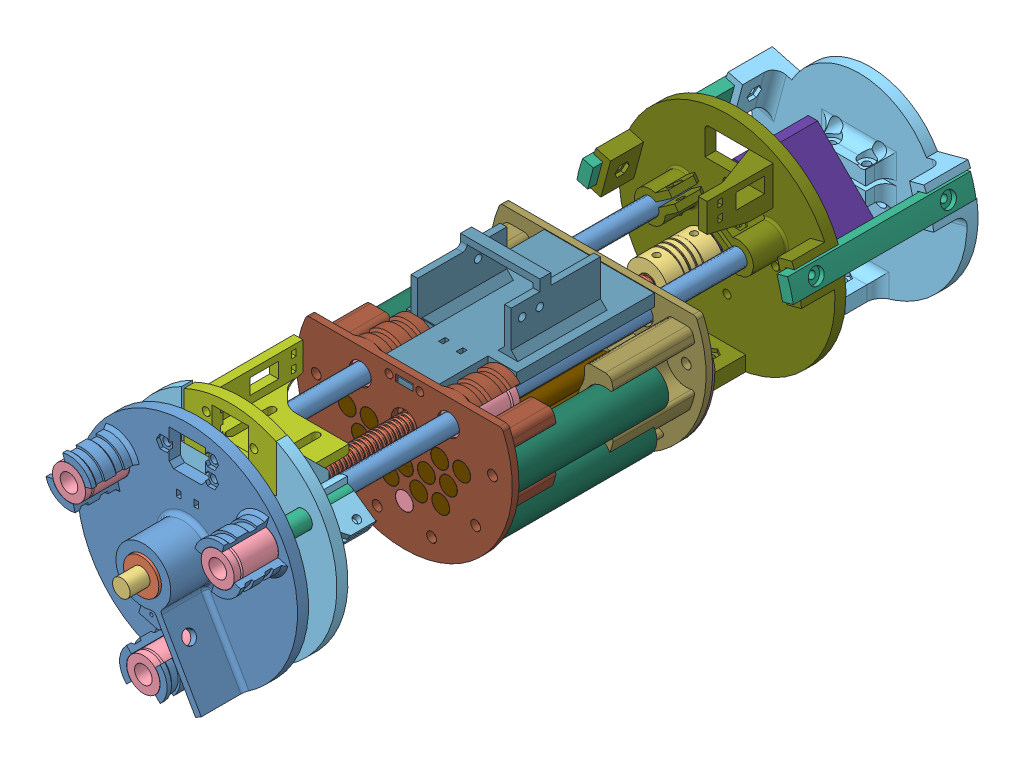
SolidWorks assembly Adjustment cabin, configuration 默认. Lengths in mm.
Overall size (100 100 340).
54 component instances, 25 part files, 87 mates.
Components (placement in the parent):
- Pogo_header_front_mount-1: Pogo_header_front_mount [默认] at (299.7292 -3.7239 87.5) size (100 100 25)
- F8-16M-1: F8-16M [默认] at (119.7292 -3.7239 108.5) x (1 0 0) z (0 -1 0) size (16 5 16)
- M8_bolt_40mm-2: M8_bolt_40mm [默认] at (-30.2708 -3.7239 78.5) x (1 0 0) z (0 -1 0) size (13 44 13)
- F8-16M-2: F8-16M [默认] at (119.7292 -3.7239 82.5) x (1 0 0) z (0 -1 0) size (16 5 16)
- LM8UU-1: LM8UU [默认] at (25.9542 15.7761 88.5) x (1 0 0) z (0 -1 0) size (15 24 15)
- LM8UU-2: LM8UU [默认] at (3.5042 -36.1854 88.5) x (-0.5 -0.866025 0) z (-0.866025 0.5 0) size (15 24 15)
- LM8UU-3: LM8UU [默认] at (-30.2708 9.2376 88.5) x (-0.5 0.866025 0) z (0.866025 0.5 0) size (15 24 15)
- Pogo_header_slider_mount-1: Pogo_header_slider_mount [默认] at (-300.2708 -153.7239 73.6245) x (-1 0 0) z (0 0 -1) size (98 93.03 21)
- 8mm_smooth_rod_45mm-1: 8mm_smooth_rod_45mm [默认] at (-26.4958 15.7761 98.6245) x (1 0 0) z (0 -1 0) size (8 45 8)
- 8mm_smooth_rod_45mm-2: 8mm_smooth_rod_45mm [默认] at (-4.0458 -36.1854 98.6245) x (-0.5 0.866025 0) z (0.866025 0.5 0) size (8 45 8)
- 8mm_smooth_rod_45mm-3: 8mm_smooth_rod_45mm [默认] at (29.7292 9.2376 98.6245) x (-0.5 -0.866025 0) z (-0.866025 0.5 0) size (8 45 8)
- Pogo_header_back_mount-2: Pogo_header_back_mount [默认] at (-449.7708 32.2761 73.6245) x (-1 0 0) z (0 0 -1) size (42 26 50)
- Acme_bearing_back-2: Acme_bearing_back [默认] at (-450.2708 -153.7239 68.6245) x (-1 0 0) z (0 0 -1) size (36.44 35.5 10)
- 608ZZ-1: 608ZZ [默认] at (-30.2708 -3.7239 55.6245) x (-1 0 0) z (0 1 0) size (22 7 22)
- Acme_bearing_front-1: Acme_bearing_front [默认] at (-450.2708 -303.7239 55.6245) x (-1 0 0) z (0 0 -1) size (36.44 35.5 16)
- Battery_mount_bearings-1: Battery_mount_bearings [默认] at (-0.2708 -3.7239 -6.0228) x (-1 0 0) z (0 0 -1) size (98 69.8 25)
- Battery_mount_acme-1: Battery_mount_acme [默认] at (-0.2708 -153.7239 -97.0228) size (98 69.8 40)
- Battery_rods_cover-1: Battery_rods_cover [默认] at (599.7292 -3.7239 -98.0228) size (98 58 1)
- Battery_mount_connector-1: Battery_mount_connector [默认] at (150.2292 11.2761 98.4772) x (1 0 0) z (0 1 0) size (50 91 30)
- LM8UU-4: LM8UU [默认] at (79.7292 6.2761 -31.0228) x (1 0 0) z (0 -1 0) size (15 24 15)
- LM8UU-5: LM8UU [默认] at (39.7292 6.2761 -31.0228) x (1 0 0) z (0 -1 0) size (15 24 15)
- 18650-1: 18650 [默认] at (-30.2708 -3.7239 -77.0228) x (1 0 0) z (0 -1 0) size (18 68 18)
- 18650-7: 18650 [默认] at (-26.2516 11.2761 -77.0228) x (0.866025 -0.5 0) z (-0.5 -0.866025 0) size (18 68 18)
- 18650-8: 18650 [默认] at (-15.2708 22.2569 -77.0228) x (0.5 -0.866025 0) z (-0.866025 -0.5 0) size (18 68 18)
- 18650-9: 18650 [默认] at (-0.2708 26.2761 -77.0228) x (0 -1 0) z (-1 0 0) size (18 68 18)
- 18650-10: 18650 [默认] at (14.7292 22.2569 -77.0228) x (-0.5 -0.866025 0) z (-0.866025 0.5 0) size (18 68 18)
- 18650-11: 18650 [默认] at (25.7099 11.2761 -77.0228) x (-0.866025 -0.5 0) z (-0.5 0.866025 0) size (18 68 18)
- 18650-12: 18650 [默认] at (29.7292 -3.7239 -77.0228) x (-1 0 0) z (0 1 0) size (18 68 18)
- Pitch_motor_mount-1: Pitch_motor_mount [默认] at (149.7292 -303.7239 -157.5) size (98 97.69 35)
- motors_17_42_34mm-1: motors_17_42_34mm [默认] at (-56.8394 52.8447 -186.5) x (0.707107 -0.707107 0) z (0 0 1) size (42.3 42.3 58)
- 8mm_rod_90mm-1: 8mm_rod_90mm [默认] at (-96.2708 -9.2239 -6.0228) x (1 0 0) z (0 -1 0) size (8 90 8)
- 8mm_rod_90mm-11: 8mm_rod_90mm [默认] at (-106.2708 -9.2239 -6.0228) x (1 0 0) z (0 -1 0) size (8 90 8)
- 8mm_rod_90mm-12: 8mm_rod_90mm [默认] at (-100.2708 -17.7239 -6.0228) x (1 0 0) z (0 -1 0) size (8 90 8)
- 8mm_rod_90mm-15: 8mm_rod_90mm [默认] at (-80.2708 -19.7239 -6.0228) x (1 0 0) z (0 -1 0) size (8 90 8)
- 8mm_rod_90mm-16: 8mm_rod_90mm [默认] at (-96.7708 -26.7239 -6.0228) x (1 0 0) z (0 -1 0) size (8 90 8)
- 8mm_rod_90mm-17: 8mm_rod_90mm [默认] at (-86.7708 -26.7239 -6.0228) x (1 0 0) z (0 -1 0) size (8 90 8)
- 8mm_rod_90mm-18: 8mm_rod_90mm [默认] at (-90.2708 -17.7239 -6.0228) x (1 0 0) z (0 -1 0) size (8 90 8)
- 8mm_rod_90mm-19: 8mm_rod_90mm [默认] at (95.7292 -9.2239 -6.0228) x (-1 0 0) z (0 1 0) size (8 90 8)
- 8mm_rod_90mm-20: 8mm_rod_90mm [默认] at (99.7292 -17.7239 -6.0228) x (-1 0 0) z (0 1 0) size (8 90 8)
- 8mm_rod_90mm-21: 8mm_rod_90mm [默认] at (96.2292 -26.7239 -6.0228) x (-1 0 0) z (0 1 0) size (8 90 8)
- 8mm_rod_90mm-22: 8mm_rod_90mm [默认] at (86.2292 -26.7239 -6.0228) x (-1 0 0) z (0 1 0) size (8 90 8)
- 8mm_rod_90mm-23: 8mm_rod_90mm [默认] at (79.7292 -19.7239 -6.0228) x (-1 0 0) z (0 1 0) size (8 90 8)
- 8mm_rod_90mm-24: 8mm_rod_90mm [默认] at (105.7292 -9.2239 -6.0228) x (-1 0 0) z (0 1 0) size (8 90 8)
- 8mm_rod_90mm-25: 8mm_rod_90mm [默认] at (89.7292 -17.7239 -6.0228) x (-1 0 0) z (0 1 0) size (8 90 8)
- 8mm_smooth_rod_245mm-1: 8mm_smooth_rod_245mm [默认] at (-180.2708 6.2761 87.5) x (1 0 0) z (0 -1 0) size (8 245 8)
- 8mm_smooth_rod_245mm-2: 8mm_smooth_rod_245mm [默认] at (-140.2708 6.2761 87.5) x (1 0 0) z (0 -1 0) size (8 245 8)
- 8mm_acme_215mm-1: 8mm_acme_215mm [默认] at (-180.2708 -3.7239 81.5) x (1 0 0) z (0 -1 0) size (9.24 218.8 8)
- Coupling_19_25_5_8mm-1: Coupling_19_25_5_8mm [默认] at (-0.2708 -3.7239 -141.5) x (1 0 0) z (0 -1 0) size (20 25 19.06)
- 8mm_threaded_rod_105mm-1: 8mm_threaded_rod_105mm [默认] at (-140.2708 -33.7239 -6.0228) x (1 0 0) z (0 -1 0) size (8 105 8)
- Pitch_motor_back_plate-1: Pitch_motor_back_plate [默认] at (299.7292 -303.7239 -217.5) size (98 83.69 20)
- Chassis_beam_middle-1: Chassis_beam_middle [默认] at (41.4188 12.6232 -216.5) x (0.258819 -0.965926 0) z (0 0 1) size (10 5.25 83)
- Chassis_beam_middle-2: Chassis_beam_middle [默认] at (4.7292 -48.2239 -216.5) x (-1 0 0) z (0 0 1) size (10 5.25 83)
- Chassis_beam_middle-3: Chassis_beam_middle [默认] at (-44.5486 2.9639 -216.5) x (0.258819 0.965926 0) z (0 0 1) size (10 5.25 83)
- Screw nut_8mm-1: Screw nut_8mm [默认] at (-0.2708 -3.7239 -97.0228) x (0.707107 -0.707107 0) z (-0.707107 -0.707107 0) size (22 15 22)
Mates (geometry in assembly coordinates):
- 同心1: concentric anti-aligned: cylinder of Pogo_header_front_mount-1 through (-0.2708 -3.7239 112.5) axis (0 0 1) radius 8.25; circle of F8-16M-1
- 重合1: coincident anti-aligned: plane of Pogo_header_front_mount-1 through (3.8292 -3.7239 108.5) normal (0 0 1); plane of F8-16M-1 through (3.7292 -3.7239 108.5) normal (0 0 -1)
- 同心2: concentric anti-aligned: cylinder of Pogo_header_front_mount-1 through (-0.2708 -3.7239 112.5) axis (0 0 1) radius 4.1; cylinder of F8-16M-2 through (-0.2708 -3.7239 87.5) axis (0 0 -1) radius 8
- 重合2: coincident anti-aligned: plane of Pogo_header_front_mount-1 through (-0.2708 -3.7239 87.5) normal (0 0 -1); plane of F8-16M-2 through (7.7292 -3.7239 87.5) normal (0 0 1)
- 同心3: concentric aligned: cylinder of M8_bolt_40mm-2 through (-0.2708 -3.7239 122.5) axis (0 0 -1) radius 4; cylinder of F8-16M-2 through (-0.2708 -3.7239 87.5) axis (0 0 -1) radius 4
- 重合3: coincident anti-aligned: plane of M8_bolt_40mm-2 through (6.2292 -3.7239 82.5) normal (0 0 1); plane of F8-16M-2 through (3.7292 -3.7239 82.5) normal (0 0 -1)
- 同心4: concentric anti-aligned: cylinder of Pogo_header_front_mount-1 through (-34.0458 15.7761 87.5) axis (0 0 1) radius 7.65; cylinder of LM8UU-1 through (-34.0458 15.7761 112.5) axis (0 0 -1) radius 7.5
- 重合4: coincident anti-aligned: plane of Pogo_header_front_mount-1 through (-26.3958 15.7761 88.5) normal (0 0 1); plane of LM8UU-1 through (-30.0458 15.7761 88.5) normal (0 0 -1)
- 同心5: concentric anti-aligned: cylinder of Pogo_header_front_mount-1 through (-0.2708 -3.7239 112.5) axis (0 0 -1) radius 50; cylinder of Pogo_header_slider_mount-1 through (-0.2708 -3.7239 68.6245) axis (0 0 1) radius 49
- 同心6: concentric aligned: cylinder of Pogo_header_slider_mount-1 through (33.5042 15.7761 53.6245) axis (0 0 1) radius 4.1; cylinder of 8mm_smooth_rod_45mm-1 through (33.5042 15.7761 53.6245) axis (0 0 1) radius 4
- 重合5: coincident aligned: plane of Pogo_header_slider_mount-1 through (33.5042 15.7832 53.6245) normal (0 0 -1); plane of 8mm_smooth_rod_45mm-1 through (37.5042 15.7761 53.6245) normal (0 0 -1)
- 重合6: coincident anti-aligned: plane of Pogo_header_slider_mount-1 through (21.2292 18.7761 73.6245) normal (-1 0 0); plane of Pogo_header_back_mount-2 through (21.2292 32.2761 73.6245) normal (1 0 0)
- 重合8: coincident anti-aligned: plane of Pogo_header_slider_mount-1 through (-300.2708 18.7761 73.6245) normal (0 1 0); plane of Pogo_header_back_mount-2 through (-6.7708 18.7761 68.6245) normal (0 -1 0)
- 重合9: coincident aligned: plane of Pogo_header_slider_mount-1 through (-0.2708 -50.4739 73.6245) normal (0 0 1); plane of Pogo_header_back_mount-2 through (0.2292 -4.2239 73.6245) normal (0 0 1)
- 同心7: concentric anti-aligned: cylinder of Pogo_header_slider_mount-1 through (-0.2708 -3.7239 73.6245) axis (0 0 1) radius 10; cylinder of Acme_bearing_back-2 through (-0.2708 -3.7239 58.6245) axis (0 0 -1) radius 11.25
- 同心8: concentric aligned: cylinder of Pogo_header_slider_mount-1 through (-0.2708 11.2761 73.6245) axis (0 0 1) radius 1.8; cylinder of Acme_bearing_back-2 through (-0.2708 11.2761 68.6245) axis (0 0 1) radius 1.8
- 同心9: concentric aligned: cylinder of Pogo_header_slider_mount-1 through (-13.2612 -11.2239 73.6245) axis (0 0 1) radius 1.8; cylinder of Acme_bearing_back-2 through (-13.2612 -11.2239 68.6245) axis (0 0 1) radius 1.8
- 重合10: coincident anti-aligned: plane of Pogo_header_slider_mount-1 through (-0.2708 -50.4739 68.6245) normal (0 0 -1); plane of Acme_bearing_back-2 through (-0.2708 -3.7239 68.6245) normal (0 0 1)
- 同心10: concentric aligned: cylinder of Acme_bearing_back-2 through (-0.2708 -3.7239 58.6245) axis (0 0 -1) radius 11.25; cylinder of 608ZZ-1 through (-0.2708 -3.7239 62.6245) axis (0 0 -1) radius 11
- 重合11: coincident anti-aligned: plane of Acme_bearing_back-2 through (-7.7708 -3.7239 62.6245) normal (0 0 -1); plane of 608ZZ-1 through (-11.2708 -3.7239 62.6245) normal (0 0 1)
- 同心11: concentric anti-aligned: cylinder of 608ZZ-1 through (-0.2708 -3.7239 62.6245) axis (0 0 -1) radius 4; cylinder of Acme_bearing_front-1 through (-0.2708 -3.7239 55.6245) axis (0 0 1) radius 6
- 同心12: concentric aligned: cylinder of Acme_bearing_back-2 through (-13.2612 -11.2239 68.6245) axis (0 0 1) radius 1.8; cylinder of Acme_bearing_front-1 through (-13.2612 -11.2239 55.6245) axis (0 0 1) radius 1.8
- 同心13: concentric aligned: cylinder of Acme_bearing_back-2 through (12.7196 -11.2239 68.6245) axis (0 0 1) radius 1.8; cylinder of Acme_bearing_front-1 through (12.7196 -11.2239 55.6245) axis (0 0 1) radius 1.8
- 同心14: concentric aligned: cylinder of Acme_bearing_back-2 through (-0.2708 11.2761 68.6245) axis (0 0 1) radius 1.8; cylinder of Acme_bearing_front-1 through (-0.2708 11.2761 55.6245) axis (0 0 1) radius 1.8
- 重合12: coincident anti-aligned: plane of 608ZZ-1 through (-10.2708 -3.7239 55.6245) normal (0 0 -1); plane of Acme_bearing_front-1 through (-0.2708 -3.7239 55.6245) normal (0 0 1)
- 同心15: concentric anti-aligned: cylinder of Pogo_header_slider_mount-1 through (-0.2708 -3.7239 68.6245) axis (0 0 1) radius 49; cylinder of Battery_mount_bearings-1 through (-0.2708 -3.7239 -6.0228) axis (0 0 -1) radius 49
- 同心16: concentric anti-aligned: cylinder of Battery_mount_bearings-1 through (-0.2708 -3.7239 -6.0228) axis (0 0 -1) radius 49; cylinder of Battery_mount_acme-1 through (-0.2708 -3.7239 -97.0228) axis (0 0 1) radius 49
- 同心17: concentric anti-aligned: cylinder of ? through (-0.2708 -3.7239 -88.4615) axis (0 0 -1) radius 50; cylinder of Battery_mount_acme-1 through (-0.2708 -3.7239 -33.8907) axis (0 0 1) radius 49
- 同心18: concentric aligned: cylinder of Battery_mount_acme-1 through (-0.2708 -3.7239 -97.0228) axis (0 0 1) radius 49; cylinder of Battery_rods_cover-1 through (-0.2708 -3.7239 -98.0228) axis (0 0 1) radius 49
- 同心19: concentric anti-aligned: cylinder of Battery_mount_acme-1 through (-0.2708 -33.7239 -97.0228) axis (0 0 -1) radius 4.1; cylinder of Battery_rods_cover-1 through (-0.2708 -33.7239 -98.0228) axis (0 0 1) radius 4.1
- 同心20: concentric anti-aligned: cylinder of Battery_mount_acme-1 through (-12.6315 -41.7661 -97.0228) axis (0 0 -1) radius 2.25; cylinder of Battery_rods_cover-1 through (-12.6315 -41.7661 -98.0228) axis (0 0 1) radius 2.25
- 重合13: coincident anti-aligned: plane of Battery_mount_acme-1 through (-0.2708 -3.7239 -97.0228) normal (0 0 -1); plane of Battery_rods_cover-1 through (-5.3541 -10.5364 -97.0228) normal (0 0 1)
- 重合14: coincident anti-aligned: plane of Battery_mount_bearings-1 through (-4.2708 11.2761 -31.0228) normal (0 1 0); plane of Battery_mount_connector-1 through (150.2292 11.2761 98.4772) normal (0 -1 0)
- 重合15: coincident anti-aligned: plane of Battery_mount_bearings-1 through (3.7292 11.2761 -31.0228) normal (-1 0 0); plane of Battery_mount_connector-1 through (3.7292 13.7761 -6.0228) normal (1 0 0)
- 重合16: coincident anti-aligned: plane of Battery_mount_bearings-1 through (-0.2708 -3.7239 -9.0228) normal (0 0 -1); plane of Battery_mount_connector-1 through (150.2292 11.2761 -9.0228) normal (0 0 1)
- 重合17: coincident anti-aligned: plane of Battery_mount_acme-1 through (-0.2708 -3.7239 -94.0228) normal (0 0 1); plane of Battery_mount_connector-1 through (150.2292 11.2761 -94.0228) normal (0 0 -1)
- 同心21: concentric aligned: cylinder of Battery_mount_bearings-1 through (19.7292 6.2761 -6.0228) axis (0 0 -1) radius 7.65; cylinder of LM8UU-4 through (19.7292 6.2761 -7.0228) axis (0 0 -1) radius 7.5
- 重合18: coincident anti-aligned: plane of Battery_mount_bearings-1 through (12.0792 6.2761 -7.0228) normal (0 0 -1); plane of LM8UU-4 through (27.2292 6.2761 -7.0228) normal (0 0 1)
- 同心22: concentric aligned: cylinder of Battery_mount_bearings-1 through (-20.2708 6.2761 -6.0228) axis (0 0 -1) radius 7.65; cylinder of LM8UU-5 through (-20.2708 6.2761 -7.0228) axis (0 0 -1) radius 7.5
- 重合19: coincident anti-aligned: plane of Battery_mount_bearings-1 through (-27.9208 6.2761 -7.0228) normal (0 0 -1); plane of LM8UU-5 through (-12.7708 6.2761 -7.0228) normal (0 0 1)
- 同心23: concentric anti-aligned: cylinder of Battery_mount_bearings-1 through (39.7292 -3.7239 -31.0228) axis (0 0 1) radius 9.35; cylinder of 18650-1 through (39.7292 -3.7239 -9.0228) axis (0 0 -1) radius 9
- 重合20: coincident anti-aligned: plane of Battery_mount_bearings-1 through (-0.2708 -3.7239 -9.0228) normal (0 0 -1); plane of 18650-1 through (48.7292 -3.7239 -9.0228) normal (0 0 1)
- 同心24: concentric anti-aligned: cylinder of Battery_mount_acme-1 through (-0.2708 -3.7239 -97.0228) axis (0 0 1) radius 49; cylinder of Pitch_motor_mount-1 through (-0.2708 -3.7239 -152.5) axis (0 0 -1) radius 49
- 同心25: concentric aligned: cylinder of Battery_mount_acme-1 through (-0.2708 -3.7239 -97.0228) axis (0 0 -1) radius 5.5; cylinder of Pitch_motor_mount-1 through (-0.2708 -3.7239 -157.5) axis (0 0 -1) radius 12.5
- 同心26: concentric aligned: cylinder of Battery_mount_acme-1 through (-20.2708 6.2761 -97.0228) axis (0 0 -1) radius 5; cylinder of Pitch_motor_mount-1 through (-20.2708 6.2761 -137.5) axis (0 0 -1) radius 4.1
- 同心27: concentric aligned: cylinder of Pitch_motor_mount-1 through (-0.2708 -3.7239 -157.5) axis (0 0 -1) radius 12.5; cylinder of motors_17_42_34mm-1 through (-0.2708 -3.7239 -133.5) axis (0 0 -1) radius 2.5
- 同心28: concentric anti-aligned: cylinder of Pitch_motor_mount-1 through (21.6495 -3.7239 -157.5) axis (0 0 -1) radius 1.8; cylinder of motors_17_42_34mm-1 through (21.6495 -3.7239 -157.5) axis (0 0 1) radius 1.5
- 重合21: coincident anti-aligned: plane of Pitch_motor_mount-1 through (-0.2708 -54.2239 -157.5) normal (0 0 -1); plane of motors_17_42_34mm-1 through (-56.8394 52.8447 -157.5) normal (0 0 1)
- 同心29: concentric aligned: cylinder of Battery_mount_acme-1 through (-16.2708 -9.2239 -82.0228) axis (0 0 1) radius 4.1; cylinder of 8mm_rod_90mm-1 through (-16.2708 -9.2239 -96.0228) axis (0 0 1) radius 4
- 重合22: coincident anti-aligned: plane of Battery_mount_acme-1 through (-16.2708 -9.2239 -96.0228) normal (0 0 1); plane of 8mm_rod_90mm-1 through (-12.2708 -9.2239 -96.0228) normal (0 0 -1)
- 同心30: concentric aligned: cylinder of Battery_mount_acme-1 through (-26.2708 -9.2239 -96.0228) axis (0 0 1) radius 4.1; cylinder of 8mm_rod_90mm-11 through (-26.2708 -9.2239 -96.0228) axis (0 0 1) radius 4
- 重合23: coincident anti-aligned: plane of Battery_mount_acme-1 through (-22.1708 -9.2239 -96.0228) normal (0 0 1); plane of 8mm_rod_90mm-11 through (-22.2708 -9.2239 -96.0228) normal (0 0 -1)
- 同心31: concentric aligned: cylinder of Battery_mount_acme-1 through (-20.2708 -17.7239 -96.0228) axis (0 0 1) radius 4.1; cylinder of 8mm_rod_90mm-12 through (-20.2708 -17.7239 -96.0228) axis (0 0 1) radius 4
- 重合24: coincident anti-aligned: plane of Battery_mount_acme-1 through (-16.1708 -17.7239 -96.0228) normal (0 0 1); plane of 8mm_rod_90mm-12 through (-16.2708 -17.7239 -96.0228) normal (0 0 -1)
- 同心32: concentric aligned: cylinder of Battery_mount_acme-1 through (-16.7708 -26.7239 -57.0228) axis (0 0 1) radius 4.1; cylinder of 8mm_rod_90mm-16 through (-16.7708 -26.7239 -96.0228) axis (0 0 1) radius 4
- 同心33: concentric aligned: cylinder of Battery_mount_acme-1 through (-6.7708 -26.7239 -96.0228) axis (0 0 1) radius 4.1; cylinder of 8mm_rod_90mm-17 through (-6.7708 -26.7239 -96.0228) axis (0 0 1) radius 4
- 同心34: concentric aligned: cylinder of Battery_mount_acme-1 through (-10.2708 -17.7239 -82.0228) axis (0 0 1) radius 4.1; cylinder of 8mm_rod_90mm-18 through (-10.2708 -17.7239 -96.0228) axis (0 0 1) radius 4
- 同心35: concentric aligned: cylinder of Battery_mount_acme-1 through (-0.2708 -19.7239 -82.0228) axis (0 0 1) radius 4.1; cylinder of 8mm_rod_90mm-15 through (-0.2708 -19.7239 -96.0228) axis (0 0 1) radius 4
- 重合25: coincident anti-aligned: plane of Battery_mount_acme-1 through (-16.7708 -26.7239 -96.0228) normal (0 0 1); plane of 8mm_rod_90mm-16 through (-12.7708 -26.7239 -96.0228) normal (0 0 -1)
- 重合27: coincident anti-aligned: plane of Battery_mount_acme-1 through (-2.6708 -26.7239 -96.0228) normal (0 0 1); plane of 8mm_rod_90mm-17 through (-2.7708 -26.7239 -96.0228) normal (0 0 -1)
- 重合28: coincident anti-aligned: plane of Battery_mount_acme-1 through (-10.2708 -17.7239 -96.0228) normal (0 0 1); plane of 8mm_rod_90mm-18 through (-6.2708 -17.7239 -96.0228) normal (0 0 -1)
- 重合29: coincident anti-aligned: plane of Battery_mount_acme-1 through (-0.2708 -19.7239 -96.0228) normal (0 0 1); plane of 8mm_rod_90mm-15 through (3.7292 -19.7239 -96.0228) normal (0 0 -1)
- 同心36: concentric aligned: cylinder of Pogo_header_slider_mount-1 through (-20.2708 6.2761 53.6245) axis (0 0 1) radius 4.1; cylinder of 8mm_smooth_rod_245mm-1 through (-20.2708 6.2761 -157.5) axis (0 0 1) radius 4
- 重合30: coincident anti-aligned: plane of Pogo_header_front_mount-1 through (-0.2708 -3.7239 87.5) normal (0 0 -1); plane of 8mm_smooth_rod_245mm-1 through (-20.2708 6.2761 87.5) normal (0 0 1)
- 同心37: concentric aligned: cylinder of Pogo_header_slider_mount-1 through (19.7292 6.2761 53.6245) axis (0 0 1) radius 4.1; cylinder of 8mm_smooth_rod_245mm-2 through (19.7292 6.2761 -157.5) axis (0 0 1) radius 4
- 重合31: coincident anti-aligned: plane of Pogo_header_front_mount-1 through (-0.2708 -3.7239 87.5) normal (0 0 -1); plane of 8mm_smooth_rod_245mm-2 through (19.7292 6.2761 87.5) normal (0 0 1)
- 同心38: concentric anti-aligned: cylinder of motors_17_42_34mm-1 through (-0.2708 -3.7239 -133.5) axis (0 0 -1) radius 2.5; cylinder of 8mm_acme_215mm-1 through (-0.2708 -3.7239 -133.5) axis (0 0 1) radius 4
- 重合32: coincident anti-aligned: plane of motors_17_42_34mm-1 through (1.4969 -5.4917 -133.5) normal (0 0 1); plane of 8mm_acme_215mm-1 through (3.7292 -3.7239 -133.5) normal (0 0 -1)
- 同心39: concentric aligned: cylinder of motors_17_42_34mm-1 through (-0.2708 -3.7239 -133.5) axis (0 0 -1) radius 2.5; cylinder of Coupling_19_25_5_8mm-1 through (-0.2708 -3.7239 -133.5) axis (0 0 -1) radius 9.5
- 重合33: coincident aligned: plane of motors_17_42_34mm-1 through (1.4969 -5.4917 -133.5) normal (0 0 1); plane of Coupling_19_25_5_8mm-1 through (-0.2708 -3.7239 -133.5) normal (0 0 1)
- 重合34: coincident aligned: plane of Pitch_motor_mount-1 through (-0.2708 -54.2239 -157.5) normal (0 0 -1); plane of 8mm_smooth_rod_245mm-2 through (23.7292 6.2761 -157.5) normal (0 0 -1)
- 同心40: concentric anti-aligned: cylinder of Battery_mount_acme-1 through (-0.2708 -33.7239 -97.0228) axis (0 0 -1) radius 4.1; cylinder of 8mm_threaded_rod_105mm-1 through (-0.2708 -33.7239 -111.0228) axis (0 0 1) radius 4
- 重合35: coincident aligned: plane of Battery_mount_bearings-1 through (-0.2708 -3.7239 -6.0228) normal (0 0 1); plane of 8mm_threaded_rod_105mm-1 through (-0.2708 -33.7239 -6.0228) normal (0 0 1)
- 同心41: concentric aligned: cylinder of Pitch_motor_mount-1 through (-0.2708 -3.7239 -152.5) axis (0 0 -1) radius 49; cylinder of Pitch_motor_back_plate-1 through (-0.2708 -3.7239 -212.5) axis (0 0 -1) radius 49
- 同心42: concentric aligned: cylinder of Pitch_motor_mount-1 through (-0.2708 -3.7239 -157.5) axis (0 0 -1) radius 12.5; cylinder of Pitch_motor_back_plate-1 through (-0.2708 -3.7239 -212.5) axis (0 0 -1) radius 4.1
- 重合36: coincident anti-aligned: plane of Pitch_motor_mount-1 through (41.2894 13.1062 -157.5) normal (0.965926 0.258819 0); plane of ? through (44.2698 1.983 -137.5) normal (-0.965926 -0.258819 0)
- 重合37: coincident aligned: plane of Pitch_motor_mount-1 through (-0.2708 -3.7239 -137.5) normal (0 0 1); plane of ? through (47.8054 8.1067 -137.5) normal (0 0 1)
- 重合38: coincident aligned: plane of Pitch_motor_back_plate-1 through (580.231 -23.7239 -207.5) normal (0 0 -1); plane of ? through (47.8054 8.1067 -207.5) normal (0 0 -1)
- 同心43: concentric aligned: cylinder of Pitch_motor_mount-1 through (42.7129 7.7936 -145) axis (0.965926 0.258819 0) radius 1.7; cylinder of ? through (47.5425 9.0877 -145) axis (0.965926 0.258819 0) radius 1.8
- 同心44: concentric anti-aligned: cylinder of Pitch_motor_back_plate-1 through (63.9632 13.4876 -218) axis (-0.965926 -0.258819 0) radius 1.7; cylinder of ? through (47.5425 9.0877 -218) axis (0.965926 0.258819 0) radius 1.8
- 重合39: coincident anti-aligned: plane of Pitch_motor_mount-1 through (41.2894 13.1062 -157.5) normal (0.965926 0.258819 0); plane of ? through (44.007 2.9639 -133.5) normal (-0.965926 -0.258819 0)
- 重合40: coincident anti-aligned: plane of Pitch_motor_mount-1 through (41.2894 13.1062 -157.5) normal (0.965926 0.258819 0); plane of Chassis_beam_middle-1 through (41.4188 12.6232 -133.5) normal (-0.965926 -0.258819 0)
- 同心46: concentric anti-aligned: cylinder of Pitch_motor_mount-1 through (42.7129 7.7936 -145) axis (0.965926 0.258819 0) radius 1.7; cylinder of Chassis_beam_middle-1 through (52.3721 10.3818 -145) axis (-0.965926 -0.258819 0) radius 1.6
- 同心47: concentric aligned: cylinder of Pitch_motor_back_plate-1 through (63.9632 13.4876 -205) axis (-0.965926 -0.258819 0) radius 1.7; cylinder of Chassis_beam_middle-1 through (52.3721 10.3818 -205) axis (-0.965926 -0.258819 0) radius 1.6
- 同心48: concentric: circle of Battery_mount_acme-1; cylinder of Screw nut_8mm-1 through (-0.2708 -3.7239 -136.9939) axis (0 0 1) radius 5.1
- 同心49: concentric: cylinder of Battery_mount_acme-1 through (5.386 -9.3807 -97.0228) axis (0 0 -1) radius 1.8; circle of Screw nut_8mm-1
- 重合41: coincident anti-aligned: plane of Battery_mount_acme-1 through (-0.2708 -3.7239 -97.0228) normal (0 0 -1); plane of Screw nut_8mm-1 through (-0.2708 -3.7239 -97.0228) normal (0 0 1)
